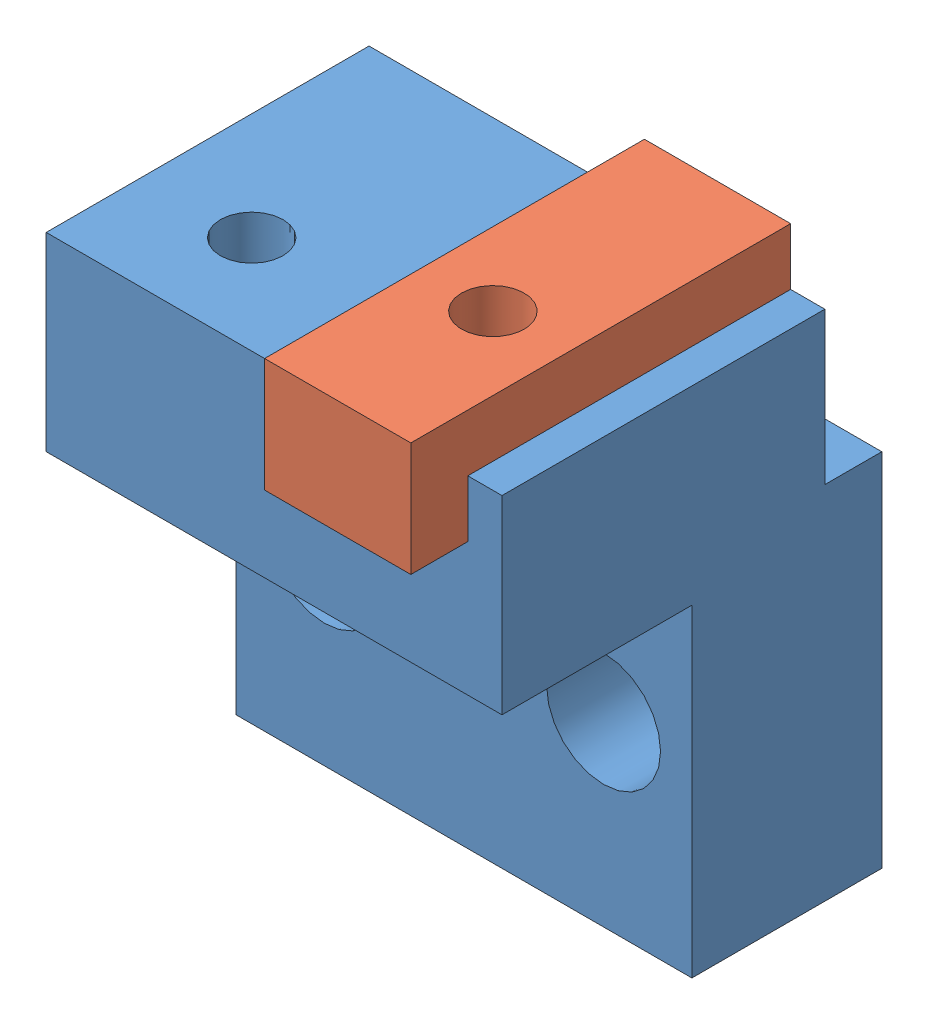
SolidWorks assembly Assem1, configuration Default. Lengths in mm.
Overall size (24 30 23).
2 component instances, 2 part files, 4 mates.
Components (placement in the parent):
- SubCarriage-1: SubCarriage [Default] at (5.8994 -40.0326 -7.7777) size (24 27 20)
- beltclamp-1: beltclamp [Default] at (5.8994 14.9674 -7.7777) x (1 0 0) z (0 1 0) size (7.7 20 6)
Mates (geometry in assembly coordinates):
- InPlace1: in place: plane of SubCarriage-1 through (5.8994 14.9674 -7.7777) normal (0 1 0); plane of ? through (0 14.9674 0) normal (0 1 0); moOrthogonalPlaneRef_w of SubCarriage-1 through (5.8994 14.9674 -7.7777) normal (0 1 0); plane of ? through (0 14.9674 0) normal (0 0 -1); plane of SubCarriage-1 through (5.8994 14.9674 -7.7777) normal (0 1 0); line of ? through (-55 0 14.9674) axis (0 1 0); plane of SubCarriage-1 through (5.8994 14.9674 -7.7777) normal (0 1 0); unknown of beltclamp-1
- Coincident1: coincident aligned: plane of SubCarriage-1; plane of beltclamp-1
- Coincident2: coincident aligned: moOrthogonalPlaneRef_w of SubCarriage-1 through (5.8994 14.9674 -7.7777) normal (0 0 -1); plane of beltclamp-1 through (5.8994 14.9674 -7.7777) normal (0 0 -1)
- Coincident3: coincident anti-aligned: moOrthogonalPlaneRef_w of SubCarriage-1 through (5.8994 14.9674 -7.7777) normal (-1 0 0); plane of beltclamp-1
